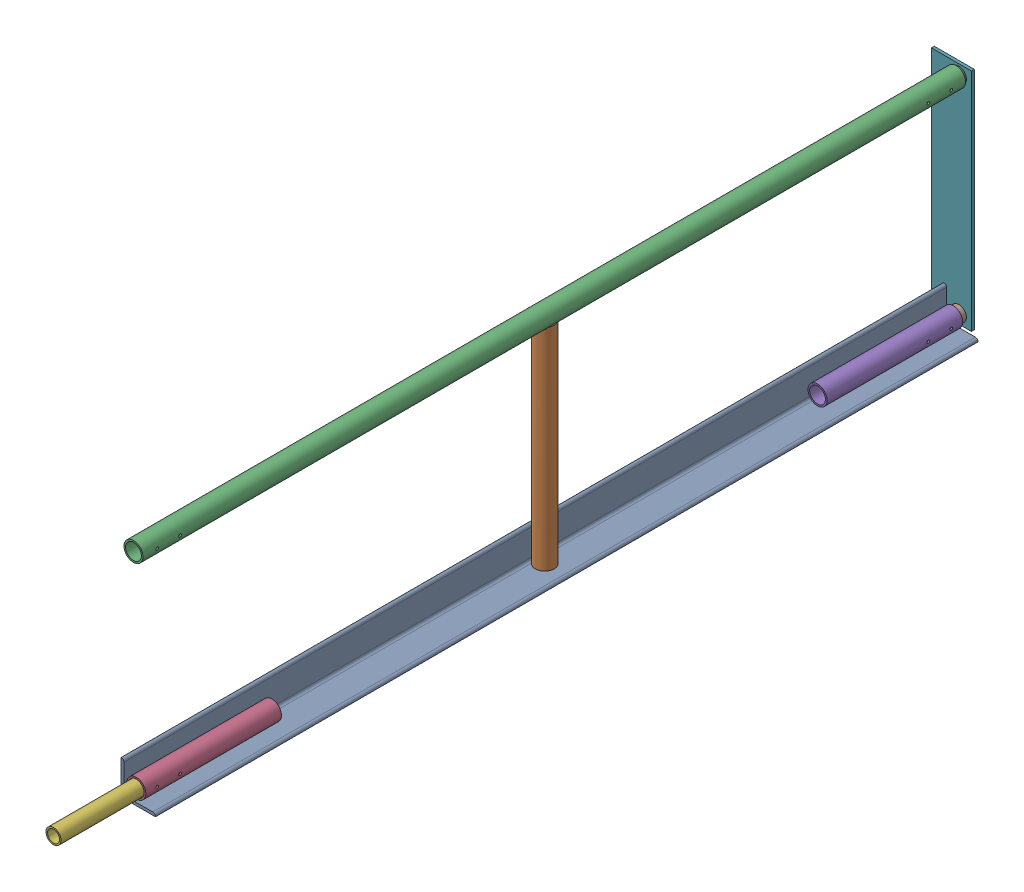
SolidWorks assembly FE-00023_ASM, configuration Default. Lengths in mm.
Overall size (109.88 508 2063.85).
13 component instances, 9 part files, 0 mates.
Components (placement in the parent):
- FE-00005_ASM-1: FE-00005_ASM [Default] at origin size (76.2 507.65 1828.8)
  - FE-00005-01-1: FE-00005-01 [Default] at origin size (76.2 76.2 1828.8)
  - FE-00005-03-1: FE-00005-03 [Default] at (27.432 6.35 914.4) size (42.16 471.23 42.16)
  - FE-00005-04-1: FE-00005-04 [Default] at (27.432 486.5688 0) size (42.16 42.16 1828.8)
  - FE-00005-02-1: FE-00005-02 [Default] at (27.432 27.432 1520.825) size (42.16 42.16 301.62)
  - FE-00005-02-2: FE-00005-02 [Default] at (27.432 27.432 307.975) x (1 0 0) z (0 0 -1) size (42.16 42.16 301.62)
- FE-00026-1: FE-00026 [Default] at (27.432 27.432 1651) size (33.4 33.4 355.6)
- FE-00018_ASM-1: FE-00018_ASM [Default] at (-33.6804 508 -6.35) x (1 0 0) z (0 0 -1) size (88.9 501.65 152.5)
  - FE-00018-03-1: FE-00018-03 [Default] at origin size (88.9 501.65 6.35)
  - FE-00018-02-1: FE-00018-02 [Default] at (61.1187 480.2188 -101.6) size (33.4 33.4 101.6)
  - FE-00018-02-2: FE-00018-02 [Default] at (61.1124 21.4312 -101.6) size (33.4 33.4 101.6)
  - FE-00018-01-1: FE-00018-01 [Default] at (23.368 63.5 29.8196) x (1 0 0) z (0 1 0) size (42.16 42.16 374.65)
  - FE-00018-04-1: FE-00018-04 [Default] at (23.368 250.825 6.35) size (19.05 374.65 2.38)
